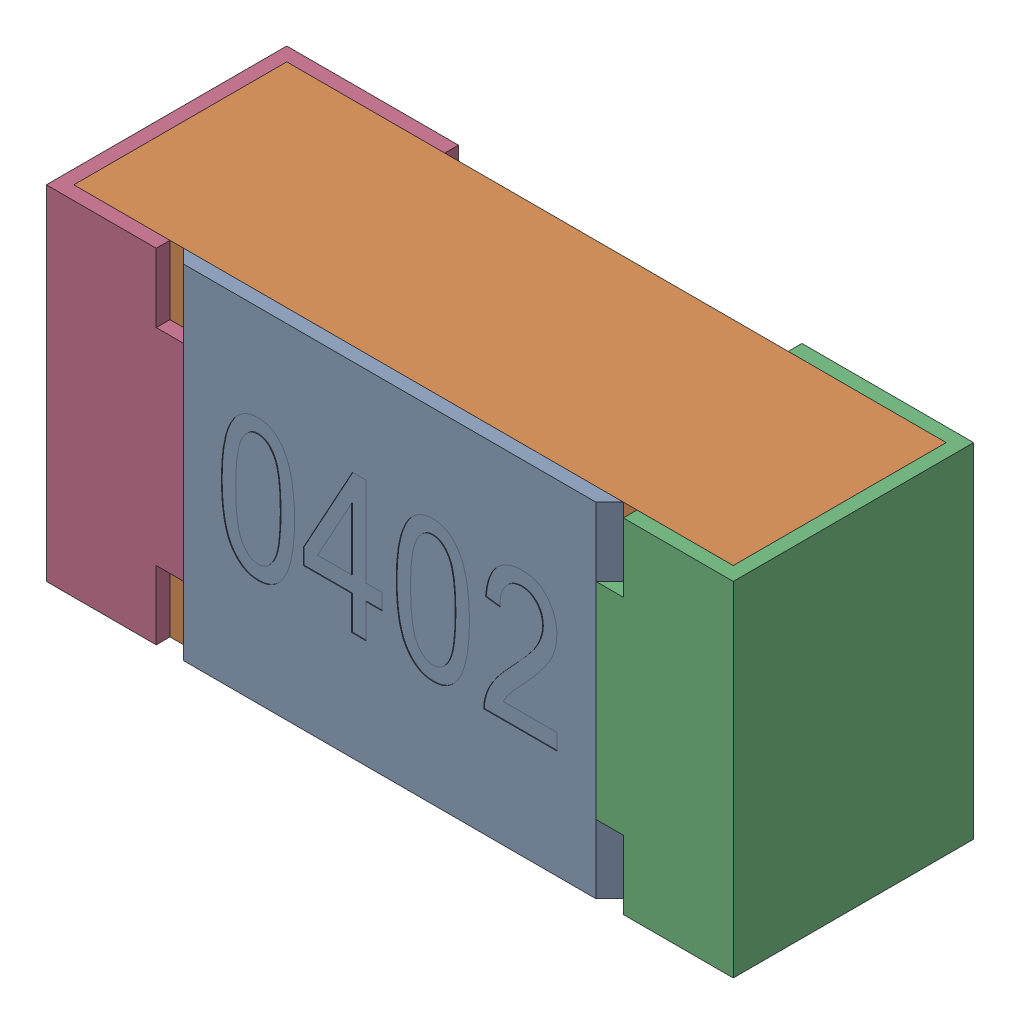
SolidWorks assembly R29, configuration Standard. Lengths in mm.
Overall size (1 0.5 0.35).
5 component instances, 4 part files, 0 mates.
Components (placement in the parent):
- R29-subassembly-1-1: R29-subassembly-1 [Standard] at (-11.3999 1.1 0) x (1 0 0) z (0 0 1) size (1 0.5 0.35)
  - User Library-R_0402-1: User Library-R_0402 [Standard] at origin size (0.64 0.5 0.02)
  - User Library-R_0402-1-1: User Library-R_0402-1 [Standard] at origin size (0.96 0.5 0.31)
  - User Library-R_0402-2-1: User Library-R_0402-2 [Standard] at origin size (0.25 0.5 0.35)
  - User Library-R_0402-3-1: User Library-R_0402-3 [Standard] at origin size (0.25 0.5 0.35)
